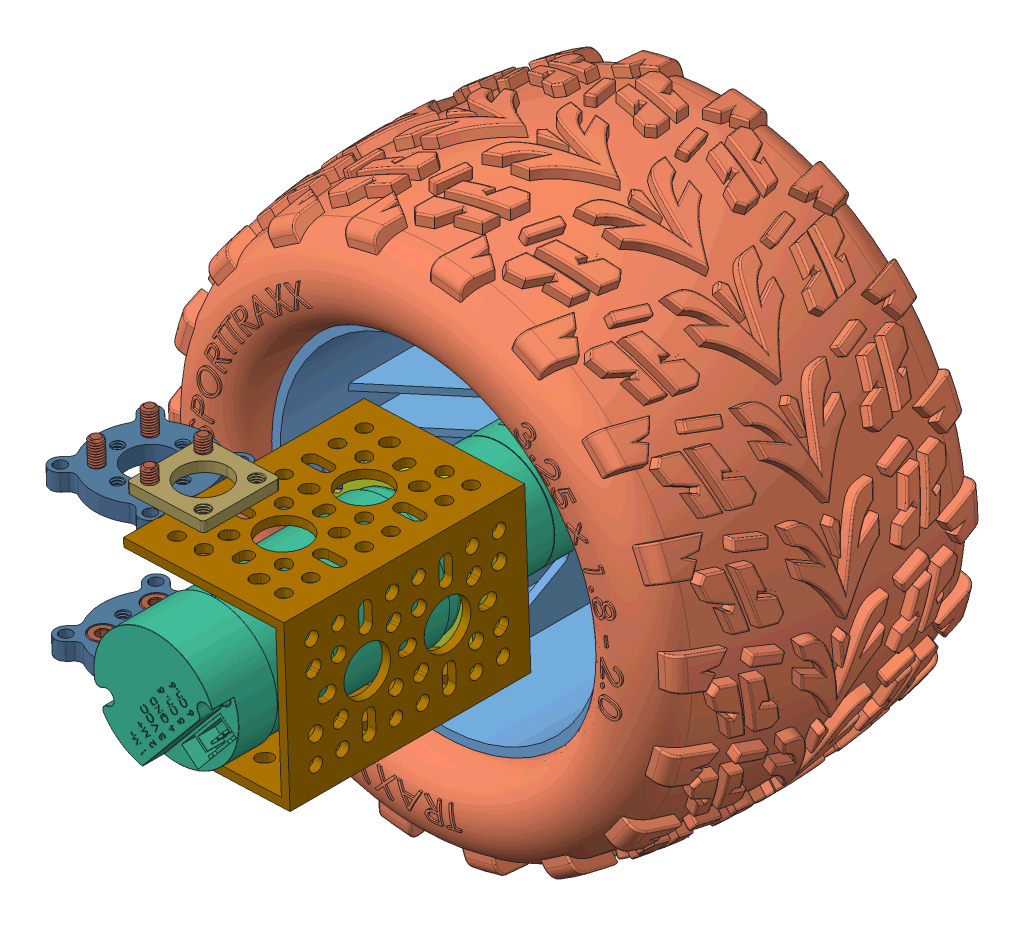
SolidWorks assembly Wheel Assembly, configuration Middle Wheel. Lengths in mm.
Overall size (166.47 166.05 178.61).
28 component instances, 13 part files, 26 mates.
Components (placement in the parent):
- Wheel-1: Wheel [Default] at (0 0 -5.7032) x (0 0 -1) z (1 0 0) size (106.88 166.05 166.47)
  - Wheel Rim-1: Wheel Rim [Default] at (-5.7009 0 0) size (78.74 101.6 101.6)
  - Wheel Tire-1: Wheel Tire [Default] at (-5.7009 -0.0005 -0.0001) size (106.88 166.05 166.47)
- 6-32_SHCS-5: 6-32_SHCS [6-32 SHCS X 1.250] at (9.1943 3.3307 1.201) x (-1 0 0) z (0 0 -1) size (5.74 5.74 35.26)
- 6-32_SHCS-6: 6-32_SHCS [6-32 SHCS X 1.250] at (-9.1943 -3.3307 1.201) x (-1 0 0) z (0 0 -1) size (5.74 5.74 35.26)
- wheel shell-1: wheel shell [Default] at (0 0 156.0711) x (-0.903132 -0.429363 0) z (0.429363 -0.903132 0) size (165.1 2.54 165.1) (hidden)
- servocity-hub-545619assembly-1: servocity-hub-545619assembly [Default] at (-0.9738 -41.3522 -6.7488) x (-0.423986 -0.905669 0) z (-0.905669 0.423986 0) size (20.57 9.62 26.29)
  - 545619-1: 545619 [Default] at (-37.8643 4.2066 16.6508) size (20.57 9.62 26.29)
  - 632110_90128A121-1: 632110_90128A121 [Default] at (-42.6268 10.2391 4.0778) x (0 0 1) z (-1 0 0) size (5.74 5.74 13.19)
- gobilda-435rpm-planetary-gearmotor-1: gobilda-435rpm-planetary-gearmotor [Default] at (0 0 8.4534) x (0.969869 0.243628 0) z (0 0 -1) size (37.5 37.5 140.72)
- gobilda-32mm-motor-clamp-1401-0043-0032-1: gobilda-32mm-motor-clamp-1401-0043-0032 [Default] at (4.3688 0.9618 57.6966) x (0.038462 -0.99926 0) z (0.99926 0.038462 0) size (43.27 8.04 47.02)
  - 1401-0043-0032-1: 1401-0043-0032 [Default] at (0.7931 12.12 -4.4026) size (43.27 8 46.5)
  - 2800-0004-0014_90128A207-1: 2800-0004-0014_90128A207 [Default] at (7.7931 12.12 -28.4026) x (0 0.161804 -0.986823) z (1 0 0) size (7 7 18.17)
- gobilda-2hole-channel-1120-0002-0072-1: gobilda-2hole-channel-1120-0002-0072 [Default] at (21.4841 0.8269 37.5767) x (-0.038462 0.99926 0) z (0.99926 0.038462 0) size (48 72 48)
- gobilda-to-actobotics-bracket-1206-0016-0004-1: gobilda-to-actobotics-bracket-1206-0016-0004 [Default] at (-40.7735 -59.4522 68.4601) x (0.038462 -0.99926 0) z (0 0 1) size (12.17 33.02 33.02)
  - 1206-0016-0004-1: 1206-0016-0004 [Default] at (-38.84 3.03 17.1166) size (5.21 33.02 33.02)
  - 2800-0004-0008_90128A207-1: 2800-0004-0008_90128A207 [Default] at (-26.84 11.03 25.1166) x (0 0 -1) z (1 0 0) size (7 7 12.17)
  - 2800-0004-0008_90128A207-2: 2800-0004-0008_90128A207 [Default] at (-26.84 11.03 9.1166) x (0 -1 0) z (1 0 0) size (7 7 12.17)
  - 2800-0004-0008_90128A207-3: 2800-0004-0008_90128A207 [Default] at (-26.84 -4.97 9.1166) x (0 0 1) z (1 0 0) size (7 7 12.17)
  - 2800-0004-0008_90128A207-4: 2800-0004-0008_90128A207 [Default] at (-26.84 -4.97 25.1166) x (0 1 0) z (1 0 0) size (7 7 12.17)
- gobilda-to-actobotics-bracket-1206-0016-0004-2: gobilda-to-actobotics-bracket-1206-0016-0004 [Default] at (-39.1673 56.3753 68.4601) x (-0.038462 0.99926 0) z (0 0 1) size (12.17 33.02 33.02)
  - 1206-0016-0004-1: 1206-0016-0004 [Default] at (-38.84 3.03 17.1166) size (5.21 33.02 33.02)
  - 2800-0004-0008_90128A207-1: 2800-0004-0008_90128A207 [Default] at (-26.84 11.03 25.1166) x (0 0 -1) z (1 0 0) size (7 7 12.17)
  - 2800-0004-0008_90128A207-2: 2800-0004-0008_90128A207 [Default] at (-26.84 11.03 9.1166) x (0 -1 0) z (1 0 0) size (7 7 12.17)
  - 2800-0004-0008_90128A207-3: 2800-0004-0008_90128A207 [Default] at (-26.84 -4.97 9.1166) x (0 0 1) z (1 0 0) size (7 7 12.17)
  - 2800-0004-0008_90128A207-4: 2800-0004-0008_90128A207 [Default] at (-26.84 -4.97 25.1166) x (0 1 0) z (1 0 0) size (7 7 12.17)
- gobilda-threaded-plate-2803.step-1: gobilda-threaded-plate-2803.step [Default] at (-24.9053 23.0592 85.5767) x (0.99926 0.038462 0) z (0 0 1) size (23 3.01 23)
- gobilda-threaded-plate-2803.step-2: gobilda-threaded-plate-2803.step [Default] at (-23.0592 -24.9053 85.5767) x (-0.99926 -0.038462 0) z (0 0 1) size (23 3.01 23)
Mates (geometry in assembly coordinates):
- Concentric1: concentric aligned: cylinder of Wheel-1/Wheel Rim-1 through (-9.1943 -3.3307 -39.3722) axis (0 0 1) radius 1.905; cylinder of 6-32_SHCS-6 through (-9.1943 -3.3307 -43.249) axis (0 0 1) radius 2.8702
- Concentric2: concentric aligned: cylinder of Wheel-1/Wheel Rim-1 through (9.1943 3.3307 -39.3722) axis (0 0 1) radius 1.905; cylinder of 6-32_SHCS-5 through (9.1943 3.3307 -43.249) axis (0 0 1) radius 2.8702
- Coincident8: coincident: point of Wheel-1/Wheel Rim-1; plane of 6-32_SHCS-6 through (-9.1943 -3.3307 -30.549) normal (0 0 1)
- Coincident9: coincident: unknown of Wheel-1/Wheel Rim-1; plane of 6-32_SHCS-5 through (9.1943 3.3307 -30.549) normal (0 0 1)
- Concentric13: concentric anti-aligned: cylinder of Wheel-1/Wheel Rim-1 through (0 0 39.3678) axis (0 0 -1) radius 1.9685; cylinder of wheel shell-1 through (0 0 153.5311) axis (0 0 1) radius 82.55
- Concentric19: concentric aligned: cylinder of Wheel-1/Wheel Rim-1 through (0 0 39.3678) axis (0 0 -1) radius 1.9685; cylinder of servocity-hub-545619assembly-1/545619-1 through (0 0 -2.5422) axis (0 0 -1) radius 3.175
- Concentric20: concentric aligned: circle of 6-32_SHCS-5; circle of servocity-hub-545619assembly-1/545619-1
- Tangent10: tangent: plane of assembly; face of Wheel-1/Wheel Rim-1; plane of servocity-hub-545619assembly-1/545619-1 through (0 0 -0.0022) normal (0 0 -1)
- Coincident18: coincident aligned: plane of Wheel-1 through (0 0 -5.7032) normal (1 0 0); plane of assembly through (0 0 0) normal (1 0 0)
- Coincident19: coincident aligned: plane of Wheel-1 through (0 0 -5.7032) normal (0 1 0); plane of assembly through (0 0 0) normal (0 1 0)
- Coincident21: coincident: unknown of Wheel-1/Wheel Tire-1
- Concentric32: concentric anti-aligned: cylinder of gobilda-435rpm-planetary-gearmotor-1 through (0 0 21.5034) axis (0 0 1) radius 16; cylinder of gobilda-32mm-motor-clamp-1401-0043-0032-1/1401-0043-0032-1 through (0 0 49.5767) axis (0 0 -1) radius 16
- Concentric35: concentric anti-aligned: cylinder of Wheel-1/Wheel Rim-1 through (0 0 39.3678) axis (0 0 -1) radius 1.9685; cylinder of gobilda-435rpm-planetary-gearmotor-1 through (0 0 -15.5466) axis (0 0 1) radius 3
- Coincident71: coincident anti-aligned: plane of gobilda-32mm-motor-clamp-1401-0043-0032-1/1401-0043-0032-1 through (20.6572 22.311 41.5767) normal (-0.038462 0.99926 0); plane of gobilda-2hole-channel-1120-0002-0072-1 through (20.6572 22.311 109.5767) normal (0.038462 -0.99926 0)
- Concentric36: concentric aligned: circle of gobilda-32mm-motor-clamp-1401-0043-0032-1/1401-0043-0032-1; circle of gobilda-2hole-channel-1120-0002-0072-1
- Concentric37: concentric aligned: circle of gobilda-32mm-motor-clamp-1401-0043-0032-1/1401-0043-0032-1; circle of gobilda-2hole-channel-1120-0002-0072-1
- Coincident72: coincident anti-aligned: plane of gobilda-to-actobotics-bracket-1206-0016-0004-2/1206-0016-0004-1 through (-40.8935 22.4438 85.5767) normal (-0.038462 0.99926 0); plane of gobilda-threaded-plate-2803.step-1 through (-24.9053 23.0592 85.5767) normal (0.038462 -0.99926 0)
- Coincident73: coincident anti-aligned: cylinder of gobilda-2hole-channel-1120-0002-0072-1 through (-16.5266 13.3743 93.5767) axis (-0.038462 0.99926 0) radius 2; circle of gobilda-threaded-plate-2803.step-1
- Concentric38: concentric aligned: circle of gobilda-to-actobotics-bracket-1206-0016-0004-2/2800-0004-0008_90128A207-4; circle of gobilda-threaded-plate-2803.step-1
- Coincident74: coincident anti-aligned: plane of gobilda-2hole-channel-1120-0002-0072-1 through (-23.0592 -24.9053 109.5767) normal (0.038462 -0.99926 0); plane of gobilda-threaded-plate-2803.step-2 through (-23.0592 -24.9053 85.5767) normal (-0.038462 0.99926 0)
- Concentric42: concentric anti-aligned: circle of gobilda-2hole-channel-1120-0002-0072-1; circle of gobilda-threaded-plate-2803.step-2
- Concentric43: concentric anti-aligned: circle of gobilda-2hole-channel-1120-0002-0072-1; circle of gobilda-threaded-plate-2803.step-2
- Coincident79: coincident anti-aligned: plane of gobilda-to-actobotics-bracket-1206-0016-0004-1/1206-0016-0004-1 through (-39.0473 -25.5207 85.5767) normal (0.038462 -0.99926 0); plane of gobilda-threaded-plate-2803.step-2 through (-23.0592 -24.9053 85.5767) normal (-0.038462 0.99926 0)
- Concentric45: concentric aligned: circle of gobilda-to-actobotics-bracket-1206-0016-0004-1/2800-0004-0008_90128A207-1; circle of gobilda-threaded-plate-2803.step-2
- Coincident80: coincident anti-aligned: plane of gobilda-2hole-channel-1120-0002-0072-1 through (-24.9053 23.0592 109.5767) normal (-0.038462 0.99926 0); plane of gobilda-threaded-plate-2803.step-1 through (-24.9053 23.0592 85.5767) normal (0.038462 -0.99926 0)
- Concentric46: concentric aligned: circle of gobilda-to-actobotics-bracket-1206-0016-0004-1/2800-0004-0008_90128A207-2; circle of gobilda-threaded-plate-2803.step-2
